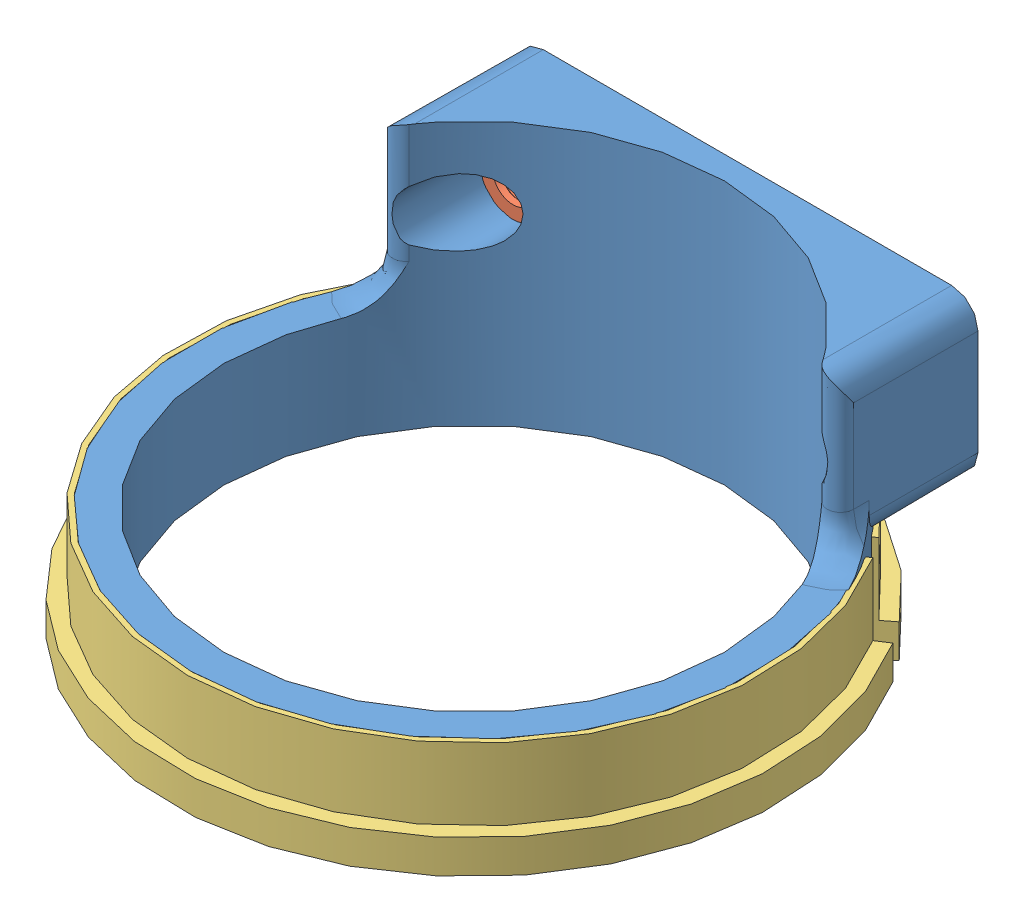
SolidWorks assembly cob_mount_assembly, configuration Default. Lengths in mm.
Overall size (64.54 20 64.54).
4 component instances, 3 part files, 6 mates.
Components (placement in the parent):
- cob_led_mount-1: cob_led_mount [Default] at (20.2172 14.0688 16.7828) size (43 20 43)
- m3_heat_set_insert_94180A331-1: m3_heat_set_insert_94180A331 [94180A331] at (6.2172 28.0688 -3.9672) x (0.928039 0.372484 0) z (-0.372484 0.928039 0) size (5.56 4.12 5.56)
- m3_heat_set_insert_94180A331-2: m3_heat_set_insert_94180A331 [94180A331] at (34.2172 28.0688 -3.9672) x (0.722417 0.691458 0) z (-0.691458 0.722417 0) size (5.56 4.12 5.56)
- cob_led_strip_cut-1: cob_led_strip_cut [Default] at (20.2172 14.0688 16.7828) x (0.790517 0 -0.61244) z (0.61244 0 0.790517) size (46 8 46)
Mates (geometry in assembly coordinates):
- Concentric1051: concentric aligned: cylinder of cob_led_mount-1 through (6.2172 28.0688 38.2828) axis (0 0 -1) radius 2.55; cylinder of m3_heat_set_insert_94180A331-1 through (6.2172 28.0688 -3.7132) axis (0 0 -1) radius 2.78
- Coincident65: coincident aligned: plane of cob_led_mount-1 through (37.7172 34.0688 -3.9672) normal (0 0 -1); plane of m3_heat_set_insert_94180A331-1 through (6.2172 28.0688 -3.9672) normal (0 0 -1)
- Concentric1061: concentric aligned: cylinder of cob_led_mount-1 through (34.2172 28.0688 38.2828) axis (0 0 -1) radius 2.55; cylinder of m3_heat_set_insert_94180A331-2 through (34.2172 28.0688 -3.7132) axis (0 0 -1) radius 2.78
- Coincident66: coincident aligned: plane of cob_led_mount-1 through (37.7172 34.0688 -3.9672) normal (0 0 -1); plane of m3_heat_set_insert_94180A331-2 through (34.2172 28.0688 -3.9672) normal (0 0 -1)
- Concentric1101: concentric aligned: cylinder of cob_led_mount-1 through (20.2172 22.0688 16.7828) axis (0 -1 0) radius 21.5; circle of cob_led_strip_cut-1
- Coincident744: coincident aligned: plane of cob_led_mount-1 through (20.2172 22.0688 16.7828) normal (0 1 0); plane of cob_led_strip_cut-1 through (38.2963 22.0688 5.1468) normal (0 1 0)
